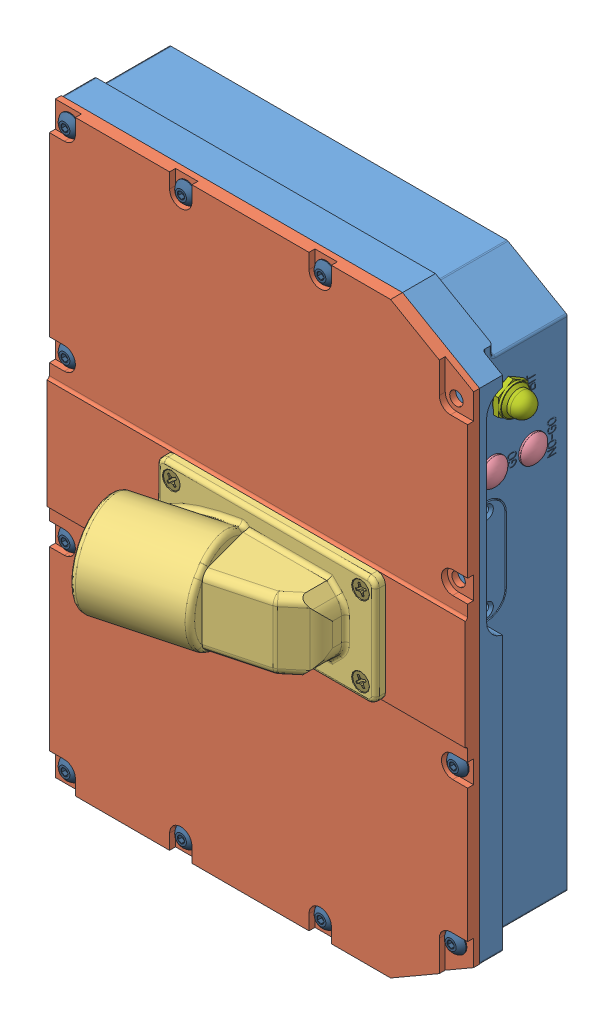
SolidWorks assembly HUD Bit Box Assembly, configuration Default. Lengths in mm.
Overall size (135.2 187.32 73.81).
39 component instances, 12 part files, 40 mates.
Components (placement in the parent):
- HUD BIT Box-1: HUD BIT Box [Default] at origin size (133.35 187.32 34.29)
- HUD BIT Box Lid-1: HUD BIT Box Lid [Default] at (0 0 34.29) size (133.35 187.32 4.6)
- HUD Camera-1: HUD Camera [Default] at (0 0 38.8937) size (72.88 34.92 34.91)
- CMC 441 XTP-1: CMC 441 XTP [CMC 441 GTP] at (130.1743 132.2705 23.8125) x (-1 0 0) z (0 0.965721 0.259583) size (10.92 8.75 8.74)
- CMC 441 XTP-2: CMC 441 XTP [CMC 441 YTP] at (130.1743 132.2705 11.1125) x (-1 0 0) z (0 0.912347 0.409418) size (10.92 8.75 8.74)
- 334-15_SLASH_X1C5-1QSA - LED, 5mm (T1.75), WHITE, 3.2V, 20mA, PTH-1: 334-15_SLASH_X1C5-1QSA - LED, 5mm (T1.75), WHITE, 3.2V, 20mA, PTH [Default] at (124.5863 132.2705 23.0425) x (0 0 1) z (0 1 0) size (5.9 33.98 5.45)
- CF18JT68R0 - RESISTOR, 68Ohms, .125W, PTH, NO LEADS-1: CF18JT68R0 - RESISTOR, 68Ohms, .125W, PTH, NO LEADS [Default] at (100.3863 132.2705 21.2645) x (-1 0 0) z (0 1 0) size (8.5 3.53 3.53)
- 334-15_SLASH_X1C5-1QSA - LED, 5mm (T1.75), WHITE, 3.2V, 20mA, PTH-2: 334-15_SLASH_X1C5-1QSA - LED, 5mm (T1.75), WHITE, 3.2V, 20mA, PTH [Default] at (124.5863 132.2705 10.3425) x (0 0 1) z (0 1 0) size (5.9 33.98 5.45)
- CF18JT68R0 - RESISTOR, 68Ohms, .125W, PTH, NO LEADS-2: CF18JT68R0 - RESISTOR, 68Ohms, .125W, PTH, NO LEADS [Default] at (100.3863 132.2705 8.5645) x (-1 0 0) z (0 1 0) size (8.5 3.53 3.53)
- N5040G 2 - DUST BOOT, GREY, .25-32, M5423-SLASH-10-01-1: N5040G 2 - DUST BOOT, GREY, .25-32, M5423-SLASH-10-01 [Default] at (133.604 150.6855 19.05) x (0 -0.866025 -0.5) z (0 -0.5 0.866025) size (9.53 8.2 11)
- 30-3UL-1: 30-3UL [Default] at (129.3812 150.6855 19.05) x (0 -1 0) z (0 0 1) size (9.53 25.53 9.53)
- 93365A130 - INSERT, 6-32, BRASS, FOR PLASTICS-1: 93365A130 - INSERT, 6-32, BRASS, FOR PLASTICS [93365A130] at (134.239 9.0805 34.29) x (0 1 0) z (1 0 0) size (5.56 4.29 5.56)
- 97763A141 - BHCS, 6-32 X .250, 18-8, BLACK-OXIDE-1: 97763A141 - BHCS, 6-32 X .250, 18-8, BLACK-OXIDE [97763A141] at (134.239 9.0805 38.0492) size (6.65 6.65 8.58)
- 91841A005 - NUT, 4-40, 18-8-1: 91841A005 - NUT, 4-40, 18-8 [91841A005] at (109.5375 96.7105 33.0994) x (0.916504 0.400026 0) z (-0.400026 0.916504 0) size (6.35 2.87 7.33)
- 90471A427 - FHS, 100DEG, 4-40 X .625, 18-8-1: 90471A427 - FHS, 100DEG, 4-40 X .625, 18-8 [90471A427] at (109.5375 96.7105 40.6856) x (0.913006 0.407946 0) z (0 0 1) size (5.38 5.38 15.88)
- 91841A005 - NUT, 4-40, 18-8-2: 91841A005 - NUT, 4-40, 18-8 [91841A005] at (109.5375 71.3105 33.0994) x (-0.2348 0.972044 0) z (-0.972044 -0.2348 0) size (6.35 2.87 7.33)
- 90471A427 - FHS, 100DEG, 4-40 X .625, 18-8-2: 90471A427 - FHS, 100DEG, 4-40 X .625, 18-8 [90471A427] at (109.5375 71.3105 40.6856) x (0.836776 0.547546 0) z (0 0 1) size (5.38 5.38 15.88)
- 91841A005 - NUT, 4-40, 18-8-3: 91841A005 - NUT, 4-40, 18-8 [91841A005] at (49.2125 96.7105 33.0994) x (-0.765841 -0.64303 0) z (0.64303 -0.765841 0) size (6.35 2.87 7.33)
- 90471A427 - FHS, 100DEG, 4-40 X .625, 18-8-3: 90471A427 - FHS, 100DEG, 4-40 X .625, 18-8 [90471A427] at (49.2125 96.7105 40.6856) x (0.760244 0.649637 0) z (0 0 1) size (5.38 5.38 15.88)
- 91841A005 - NUT, 4-40, 18-8-4: 91841A005 - NUT, 4-40, 18-8 [91841A005] at (49.2125 71.3105 33.0994) x (-0.702568 -0.711617 0) z (0.711617 -0.702568 0) size (6.35 2.87 7.33)
- 90471A427 - FHS, 100DEG, 4-40 X .625, 18-8-4: 90471A427 - FHS, 100DEG, 4-40 X .625, 18-8 [90471A427] at (49.2125 71.3105 40.6856) x (0.69638 0.717673 0) z (0 0 1) size (5.38 5.38 15.88)
- 97763A141 - BHCS, 6-32 X .250, 18-8, BLACK-OXIDE-2: 97763A141 - BHCS, 6-32 X .250, 18-8, BLACK-OXIDE [97763A141] at (11.1125 109.4105 38.0492) size (6.65 6.65 8.58)
- 97763A141 - BHCS, 6-32 X .250, 18-8, BLACK-OXIDE-3: 97763A141 - BHCS, 6-32 X .250, 18-8, BLACK-OXIDE [97763A141] at (11.1125 58.6105 38.0492) size (6.65 6.65 8.58)
- 97763A141 - BHCS, 6-32 X .250, 18-8, BLACK-OXIDE-4: 97763A141 - BHCS, 6-32 X .250, 18-8, BLACK-OXIDE [97763A141] at (11.1125 -4.8895 38.0492) size (6.65 6.65 8.58)
- 97763A141 - BHCS, 6-32 X .250, 18-8, BLACK-OXIDE-5: 97763A141 - BHCS, 6-32 X .250, 18-8, BLACK-OXIDE [97763A141] at (48.26 -4.8895 38.0492) size (6.65 6.65 8.58)
- 97763A141 - BHCS, 6-32 X .250, 18-8, BLACK-OXIDE-6: 97763A141 - BHCS, 6-32 X .250, 18-8, BLACK-OXIDE [97763A141] at (92.71 -4.8895 38.0492) size (6.65 6.65 8.58)
- 97763A141 - BHCS, 6-32 X .250, 18-8, BLACK-OXIDE-7: 97763A141 - BHCS, 6-32 X .250, 18-8, BLACK-OXIDE [97763A141] at (11.1125 172.9105 38.0492) size (6.65 6.65 8.58)
- 97763A141 - BHCS, 6-32 X .250, 18-8, BLACK-OXIDE-8: 97763A141 - BHCS, 6-32 X .250, 18-8, BLACK-OXIDE [97763A141] at (134.9375 58.6105 38.0492) size (6.65 6.65 8.58)
- 97763A141 - BHCS, 6-32 X .250, 18-8, BLACK-OXIDE-9: 97763A141 - BHCS, 6-32 X .250, 18-8, BLACK-OXIDE [97763A141] at (92.71 172.9105 38.0492) size (6.65 6.65 8.58)
- 97763A141 - BHCS, 6-32 X .250, 18-8, BLACK-OXIDE-10: 97763A141 - BHCS, 6-32 X .250, 18-8, BLACK-OXIDE [97763A141] at (48.26 172.9105 38.0492) size (6.65 6.65 8.58)
- 93365A130 - INSERT, 6-32, BRASS, FOR PLASTICS-2: 93365A130 - INSERT, 6-32, BRASS, FOR PLASTICS [93365A130] at (11.1125 109.4105 34.29) x (0 1 0) z (1 0 0) size (5.56 4.29 5.56)
- 93365A130 - INSERT, 6-32, BRASS, FOR PLASTICS-3: 93365A130 - INSERT, 6-32, BRASS, FOR PLASTICS [93365A130] at (11.1125 58.6105 34.29) x (0 1 0) z (1 0 0) size (5.56 4.29 5.56)
- 93365A130 - INSERT, 6-32, BRASS, FOR PLASTICS-4: 93365A130 - INSERT, 6-32, BRASS, FOR PLASTICS [93365A130] at (11.1125 -4.8895 34.29) x (0 1 0) z (1 0 0) size (5.56 4.29 5.56)
- 93365A130 - INSERT, 6-32, BRASS, FOR PLASTICS-5: 93365A130 - INSERT, 6-32, BRASS, FOR PLASTICS [93365A130] at (48.26 -4.8895 34.29) x (0 1 0) z (1 0 0) size (5.56 4.29 5.56)
- 93365A130 - INSERT, 6-32, BRASS, FOR PLASTICS-6: 93365A130 - INSERT, 6-32, BRASS, FOR PLASTICS [93365A130] at (92.71 -4.8895 34.29) x (0 1 0) z (1 0 0) size (5.56 4.29 5.56)
- 93365A130 - INSERT, 6-32, BRASS, FOR PLASTICS-7: 93365A130 - INSERT, 6-32, BRASS, FOR PLASTICS [93365A130] at (11.1125 172.9105 34.29) x (0 1 0) z (1 0 0) size (5.56 4.29 5.56)
- 93365A130 - INSERT, 6-32, BRASS, FOR PLASTICS-8: 93365A130 - INSERT, 6-32, BRASS, FOR PLASTICS [93365A130] at (134.9375 58.6105 34.29) x (0 1 0) z (1 0 0) size (5.56 4.29 5.56)
- 93365A130 - INSERT, 6-32, BRASS, FOR PLASTICS-9: 93365A130 - INSERT, 6-32, BRASS, FOR PLASTICS [93365A130] at (92.71 172.9105 34.29) x (0 1 0) z (1 0 0) size (5.56 4.29 5.56)
- 93365A130 - INSERT, 6-32, BRASS, FOR PLASTICS-10: 93365A130 - INSERT, 6-32, BRASS, FOR PLASTICS [93365A130] at (48.26 172.9105 34.29) x (0 1 0) z (1 0 0) size (5.56 4.29 5.56)
Mates (geometry in assembly coordinates):
- Coincident34: coincident anti-aligned: plane of HUD BIT Box-1 through (133.35 4.5215 23.8125) normal (1 0 0); circle of CMC 441 XTP-1
- Concentric20: concentric aligned: cylinder of CMC 441 XTP-1 through (130.1743 132.2705 23.8125) axis (-1 0 0) radius 3.0472; cylinder of 334-15_SLASH_X1C5-1QSA - LED, 5mm (T1.75), WHITE, 3.2V, 20mA, PTH-1 through (133.5673 132.2705 23.8125) axis (-1 0 0) radius 2.5
- Coincident43: coincident aligned: plane of CMC 441 XTP-1 through (124.9673 131.3474 27.2467) normal (-1 0 0); plane of 334-15_SLASH_X1C5-1QSA - LED, 5mm (T1.75), WHITE, 3.2V, 20mA, PTH-1 through (124.9673 132.2705 23.8125) normal (-1 0 0)
- Coincident35: coincident anti-aligned: plane of HUD BIT Box-1 through (133.35 4.5215 23.8125) normal (1 0 0); circle of CMC 441 XTP-2
- Concentric21: concentric aligned: cylinder of CMC 441 XTP-2 through (130.1743 132.2705 11.1125) axis (-1 0 0) radius 3.0472; cylinder of 334-15_SLASH_X1C5-1QSA - LED, 5mm (T1.75), WHITE, 3.2V, 20mA, PTH-2 through (133.5673 132.2705 11.1125) axis (-1 0 0) radius 2.5
- Coincident41: coincident anti-aligned: plane of HUD BIT Box-1 through (133.35 4.5215 23.8125) normal (1 0 0); plane of N5040G 2 - DUST BOOT, GREY, .25-32, M5423-SLASH-10-01-1 through (133.35 153.0668 14.9256) normal (-1 0 0)
- Parallel4: parallel aligned: plane of HUD BIT Box-1 through (0 0 34.29) normal (0 0 1); plane of N5040G 2 - DUST BOOT, GREY, .25-32, M5423-SLASH-10-01-1 through (135.1915 153.4351 23.8125) normal (0 0 1)
- Concentric18: concentric anti-aligned: cylinder of HUD BIT Box-1 through (133.35 150.6855 19.05) axis (1 0 0) radius 3.5712; cylinder of 30-3UL-1 through (135.7312 150.6855 19.05) axis (-1 0 0) radius 3.175
- Coincident39: coincident: plane of HUD BIT Box-1 through (129.3812 150.6855 19.05) normal (-1 0 0); plane of ? through (66.675 163.83 279.4) normal (0 0 1)
- Coincident40: coincident anti-aligned: plane of HUD BIT Box-1 through (129.3812 150.6855 19.05) normal (-1 0 0); plane of 30-3UL-1 through (129.3812 150.6855 19.05) normal (1 0 0)
- Parallel2: parallel anti-aligned: plane of HUD BIT Box-1 through (113.8746 172.9105 -189.6815) normal (0 -1 0); plane of 30-3UL-1 through (114.0143 148.1614 17.4625) normal (0 1 0)
- Coincident42: coincident: plane of HUD BIT Box-1 through (128.5875 164.416 -213.1038) normal (-1 0 0); plane of 30-3UL-1 through (129.3812 150.6855 19.05) normal (1 0 0)
- ProfileCenter1: profile center anti-aligned: plane of CF18JT68R0 - RESISTOR, 68Ohms, .125W, PTH, NO LEADS-1 through (99.5863 132.2705 21.2645) normal (1 0 0); plane of 334-15_SLASH_X1C5-1QSA - LED, 5mm (T1.75), WHITE, 3.2V, 20mA, PTH-1 through (99.5863 132.2705 23.0425) normal (-1 0 0)
- Coincident46: coincident aligned: plane of 334-15_SLASH_X1C5-1QSA - LED, 5mm (T1.75), WHITE, 3.2V, 20mA, PTH-1 through (124.9673 132.2705 23.8125) normal (-1 0 0); plane of 334-15_SLASH_X1C5-1QSA - LED, 5mm (T1.75), WHITE, 3.2V, 20mA, PTH-2 through (124.9673 132.2705 11.1125) normal (-1 0 0)
- Coincident47: coincident aligned: plane of 334-15_SLASH_X1C5-1QSA - LED, 5mm (T1.75), WHITE, 3.2V, 20mA, PTH-1 through (124.9673 131.7705 22.5425) normal (0 -1 0); plane of 334-15_SLASH_X1C5-1QSA - LED, 5mm (T1.75), WHITE, 3.2V, 20mA, PTH-2 through (124.9673 131.7705 9.8425) normal (0 -1 0)
- ProfileCenter2: profile center anti-aligned: plane of CF18JT68R0 - RESISTOR, 68Ohms, .125W, PTH, NO LEADS-2 through (99.5863 132.2705 8.5645) normal (1 0 0); plane of 334-15_SLASH_X1C5-1QSA - LED, 5mm (T1.75), WHITE, 3.2V, 20mA, PTH-2 through (99.5863 132.2705 10.3425) normal (-1 0 0)
- Concentric22: concentric aligned: cylinder of HUD BIT Box-1 through (134.239 9.0805 34.29) axis (0 0 1) radius 2.5273; cylinder of 93365A130 - INSERT, 6-32, BRASS, FOR PLASTICS-1 through (134.239 9.0805 34.29) axis (0 0 1) radius 2.5273
- Coincident48: coincident aligned: plane of HUD BIT Box-1 through (0 0 34.29) normal (0 0 1); plane of 93365A130 - INSERT, 6-32, BRASS, FOR PLASTICS-1 through (134.239 9.0805 34.29) normal (0 0 1)
- Concentric23: concentric aligned: cylinder of HUD BIT Box-1 through (134.239 9.0805 34.29) axis (0 0 1) radius 2.5273; cylinder of 97763A141 - BHCS, 6-32 X .250, 18-8, BLACK-OXIDE-1 through (134.239 9.0805 38.0492) axis (0 0 1) radius 3.3274
- Coincident49: coincident anti-aligned: plane of HUD BIT Box Lid-1 through (136.3916 9.0805 36.195) normal (0 0 1); plane of 97763A141 - BHCS, 6-32 X .250, 18-8, BLACK-OXIDE-1 through (134.239 5.7531 36.195) normal (0 0 -1)
- InPlace1: in place: plane of HUD BIT Box Lid-1 through (0 0 38.8937) normal (0 0 1); plane of HUD Camera-1 through (0 0 38.8937) normal (0 0 1); moOrthogonalPlaneRef_w of HUD BIT Box Lid-1 through (0 0 38.8937) normal (0 0 1); plane of HUD Camera-1 through (0 0 38.8937) normal (0 1 0); plane of HUD BIT Box Lid-1 through (0 0 38.8937) normal (0 0 1); plane of HUD Camera-1 through (0 0 38.8937) normal (1 0 0); plane of HUD BIT Box Lid-1 through (0 0 38.8937) normal (0 0 1); unknown of HUD Camera-1
- Coincident50: coincident aligned: plane of HUD BIT Box Lid-1; plane of HUD Camera-1
- Coincident51: coincident aligned: moOrthogonalPlaneRef_w of HUD BIT Box Lid-1 through (0 0 38.8937) normal (0 1 0); plane of HUD Camera-1 through (0 0 38.8937) normal (0 1 0)
- Coincident52: coincident anti-aligned: moOrthogonalPlaneRef_w of HUD BIT Box Lid-1 through (0 0 38.8937) normal (-1 0 0); plane of HUD Camera-1 through (0 0 38.8937) normal (1 0 0)
- Concentric24: concentric anti-aligned: cylinder of HUD BIT Box Lid-1 through (109.5375 96.7105 38.8937) axis (0 0 1) radius 1.7272; circle of 91841A005 - NUT, 4-40, 18-8-1
- Coincident53: coincident anti-aligned: plane of HUD BIT Box Lid-1 through (0 0 34.29) normal (0 0 -1); plane of 91841A005 - NUT, 4-40, 18-8-1 through (107.3609 93.7604 34.29) normal (0 0 1)
- Concentric25: concentric aligned: circle of 91841A005 - NUT, 4-40, 18-8-1; cone of 90471A427 - FHS, 100DEG, 4-40 X .625, 18-8-1 through (109.5375 96.7105 41.9302) axis (0 0 -1)
- Coincident54: coincident aligned: cone of HUD Camera-1 through (109.5375 96.7105 42.0688) axis (0 0 -1); cone of 90471A427 - FHS, 100DEG, 4-40 X .625, 18-8-1 through (109.5375 96.7105 41.9302) axis (0 0 -1)
- Concentric26: concentric aligned: circle of 91841A005 - NUT, 4-40, 18-8-2; cone of 90471A427 - FHS, 100DEG, 4-40 X .625, 18-8-2 through (109.5375 71.3105 41.9302) axis (0 0 -1)
- Concentric27: concentric aligned: cone of HUD Camera-1 through (109.5375 71.3105 42.0688) axis (0 0 -1); circle of 91841A005 - NUT, 4-40, 18-8-2
- Coincident55: coincident anti-aligned: plane of HUD BIT Box Lid-1 through (0 0 34.29) normal (0 0 -1); plane of 91841A005 - NUT, 4-40, 18-8-2 through (112.0648 68.6547 34.29) normal (0 0 1)
- Coincident56: coincident aligned: cone of HUD Camera-1 through (109.5375 71.3105 42.0688) axis (0 0 -1); cone of 90471A427 - FHS, 100DEG, 4-40 X .625, 18-8-2 through (109.5375 71.3105 41.9302) axis (0 0 -1)
- Concentric28: concentric aligned: circle of 91841A005 - NUT, 4-40, 18-8-3; cone of 90471A427 - FHS, 100DEG, 4-40 X .625, 18-8-3 through (49.2125 96.7105 41.9302) axis (0 0 -1)
- Coincident57: coincident anti-aligned: plane of HUD BIT Box Lid-1 through (0 0 34.29) normal (0 0 -1); plane of 91841A005 - NUT, 4-40, 18-8-3 through (50.4653 100.156 34.29) normal (0 0 1)
- Concentric29: concentric aligned: cone of HUD Camera-1 through (49.2125 96.7105 42.0688) axis (0 0 -1); circle of 91841A005 - NUT, 4-40, 18-8-3
- Coincident58: coincident aligned: cone of HUD Camera-1 through (49.2125 96.7105 42.0688) axis (0 0 -1); cone of 90471A427 - FHS, 100DEG, 4-40 X .625, 18-8-3 through (49.2125 96.7105 41.9302) axis (0 0 -1)
- Concentric30: concentric aligned: circle of 91841A005 - NUT, 4-40, 18-8-4; cone of 90471A427 - FHS, 100DEG, 4-40 X .625, 18-8-4 through (49.2125 71.3105 41.9302) axis (0 0 -1)
- Coincident59: coincident anti-aligned: plane of HUD BIT Box Lid-1 through (0 0 34.29) normal (0 0 -1); plane of 91841A005 - NUT, 4-40, 18-8-4 through (50.1387 74.8578 34.29) normal (0 0 1)
- Concentric31: concentric aligned: cone of HUD Camera-1 through (49.2125 71.3105 42.0688) axis (0 0 -1); circle of 91841A005 - NUT, 4-40, 18-8-4
- Coincident60: coincident aligned: cone of HUD Camera-1 through (49.2125 71.3105 42.0688) axis (0 0 -1); cone of 90471A427 - FHS, 100DEG, 4-40 X .625, 18-8-4 through (49.2125 71.3105 41.9302) axis (0 0 -1)
